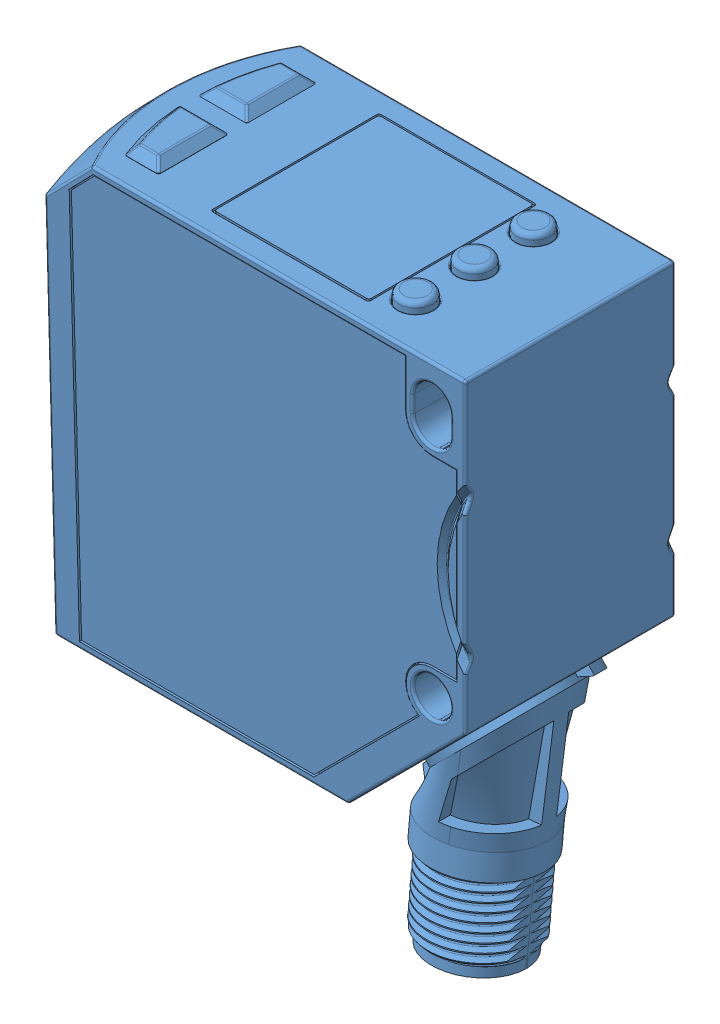
SolidWorks assembly 46CLR, configuration Default. Lengths in mm.
Overall size (50.23 69.33 25.17).
2 component instances, 1 part files, 2 mates.
Components (placement in the parent):
- 46CLR-1: 46CLR [Sensor] at (41.4161 9.9983 49.4945) size (50.23 51.65 25.17)
- 46CLR-2: 46CLR [Connection] at (39.8681 8.4502 49.655) x (0.005344 -0.994656 0.103101) z (-0.103101 -0.103101 -0.989313) size (28.81 13.66 15.69)
Mates (geometry in assembly coordinates):
- Concentric1: concentric aligned: circle of 46CLR-1; circle of 46CLR-2
- Coincident2: coincident anti-aligned: plane of 46CLR-1 through (33.4965 16.3615 49.4945) normal (0.707107 -0.707107 0); plane of 46CLR-2 through (33.4965 16.3615 49.4945) normal (-0.707107 0.707107 0)
